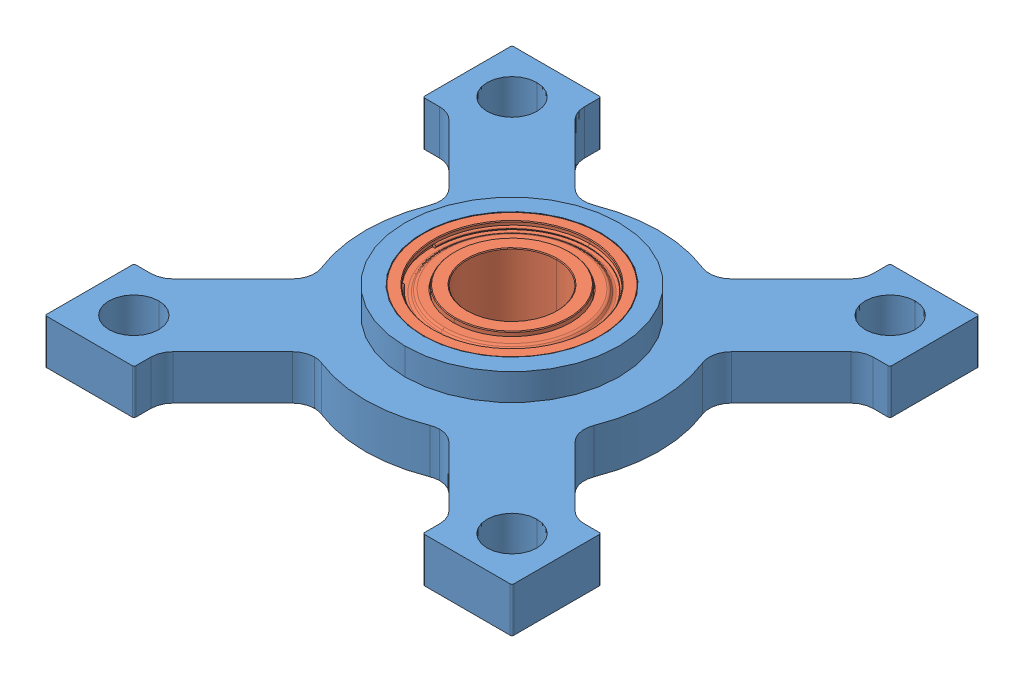
SolidWorks assembly 535110 assembly - Pillow, configuration Default. Lengths in mm.
Overall size (33.27 5.08 33.27).
3 component instances, 2 part files, 0 mates.
Components (placement in the parent):
- 535110 assembly - Pillow.STEP-1: 535110 assembly - Pillow.STEP [Default] at origin size (33.27 5.08 33.27)
  - 535110.STEP-1: 535110.STEP [Default] at (6.6273 15.2478 28.3097) size (33.27 5.08 33.27)
  - 535020.STEP-1: 535020.STEP [Default] at (6.6273 17.9338 28.3097) size (12.7 4.76 12.7)
